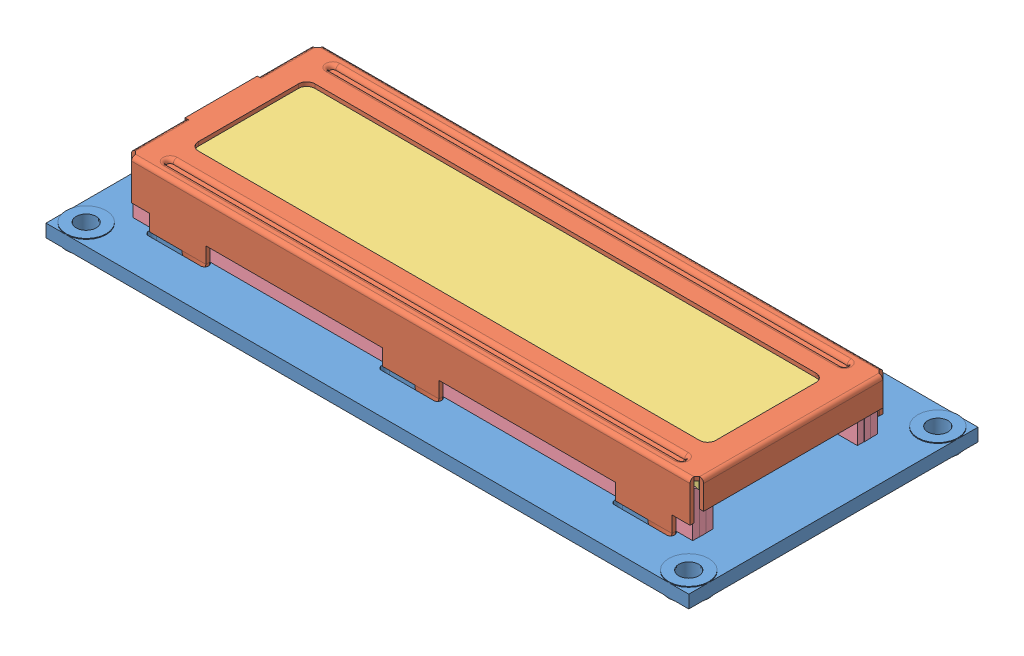
SolidWorks assembly 1602_LCD, configuration Default. Lengths in mm.
Overall size (80 10.64 36).
5 component instances, 4 part files, 16 mates.
Components (placement in the parent):
- LCD_PCB-1: LCD_PCB [Default] at (-1.4055 -3.4444 3.0818) size (80 1.8 36)
- metal_casing-1: metal_casing [Default] at (-1.5055 3.0556 3.5818) size (71.2 10.64 25.26)
- LCD-1: LCD [Default] at (-1.6055 1.9556 3.5818) size (70.3 2.1 22)
- conductors-1: conductors [Default] at (-1.7555 -0.6944 13.8318) size (69.7 5.5 2.5)
- conductors-2: conductors [Default] at (-1.7555 -0.6944 -6.6682) size (69.7 5.5 2.5)
Mates (geometry in assembly coordinates):
- Coincident1: coincident anti-aligned: plane of ? through (33.0945 -0.4444 12.5818) normal (0 0 1); plane of conductors-1 through (-1.7555 -0.6944 12.5818) normal (0 0 -1)
- Coincident2: coincident anti-aligned: plane of LCD_PCB-1 through (-1.4055 -3.4444 3.0818) normal (0 1 0); plane of ? through (-1.7555 -3.4444 3.5818) normal (0 -1 0)
- Coincident4: coincident anti-aligned: plane of ? through (33.0945 -0.4444 -5.4182) normal (0 0 -1); plane of conductors-2 through (-1.7555 -0.6944 -5.4182) normal (0 0 1)
- Coincident5: coincident anti-aligned: plane of ? through (33.0945 -0.4444 12.5818) normal (0 0 1); plane of conductors-1 through (-1.7555 -0.6944 12.5818) normal (0 0 -1)
- Coincident6: coincident anti-aligned: plane of LCD_PCB-1 through (-1.4055 -3.4444 3.0818) normal (0 1 0); plane of conductors-1 through (-36.6055 -3.4444 14.2318) normal (0 -1 0)
- Coincident7: coincident anti-aligned: plane of LCD_PCB-1 through (-1.4055 -3.4444 3.0818) normal (0 1 0); plane of conductors-2 through (-36.6055 -3.4444 -6.2682) normal (0 -1 0)
- Coincident8: coincident anti-aligned: plane of LCD_PCB-1 through (-1.4055 -3.4444 3.0818) normal (0 1 0); plane of metal_casing-1 through (-1.5055 -3.4444 3.5818) normal (0 -1 0)
- Distance3: distance = 0.1 mm anti-aligned: plane of metal_casing-1 through (-1.5055 3.0556 3.5818) normal (0 -1 0); plane of LCD-1 through (-1.6055 2.9556 3.5818) normal (0 1 0)
- Coincident10: coincident aligned: plane of ? through (-36.6055 -0.4444 -5.4182) normal (-1 0 0); plane of conductors-1 through (-36.6055 2.0556 14.2318) normal (-1 0 0)
- Coincident11: coincident aligned: plane of ? through (-36.6055 -0.4444 -5.4182) normal (-1 0 0); plane of conductors-2 through (-36.6055 2.0556 -6.2682) normal (-1 0 0)
- Coincident12: coincident aligned: plane of ? through (-36.6055 -0.4444 -5.4182) normal (-1 0 0); plane of LCD-1 through (-36.6055 2.9556 -7.4182) normal (-1 0 0)
- Coincident13: coincident anti-aligned: plane of metal_casing-1 through (-36.2555 -1.4444 15.0818) normal (0 0 -1); plane of conductors-1 through (-1.7555 -0.6944 15.0818) normal (0 0 1)
- Coincident16: coincident aligned: plane of ? through (33.0945 -0.4444 12.5818) normal (0 0 1); plane of LCD-1 through (33.3945 0.8556 12.5818) normal (0 0 1)
- Coincident18: coincident anti-aligned: plane of LCD_PCB-1 through (-33.6555 -5.0444 -7.9182) normal (0 0 -1); plane of metal_casing-1 through (33.2445 -1.4444 -7.9182) normal (0 0 1)
- Distance2: distance = 0.5 mm aligned: plane of LCD_PCB-1 through (38.5945 -5.0444 -14.9182) normal (1 0 0); plane of ? through (38.0945 -3.4444 3.5818) normal (1 0 0)
- Coincident21: coincident anti-aligned: plane of metal_casing-1 through (-36.6055 -1.4444 -7.5682) normal (1 0 0); plane of LCD-1 through (-36.6055 2.9556 -7.4182) normal (-1 0 0)
